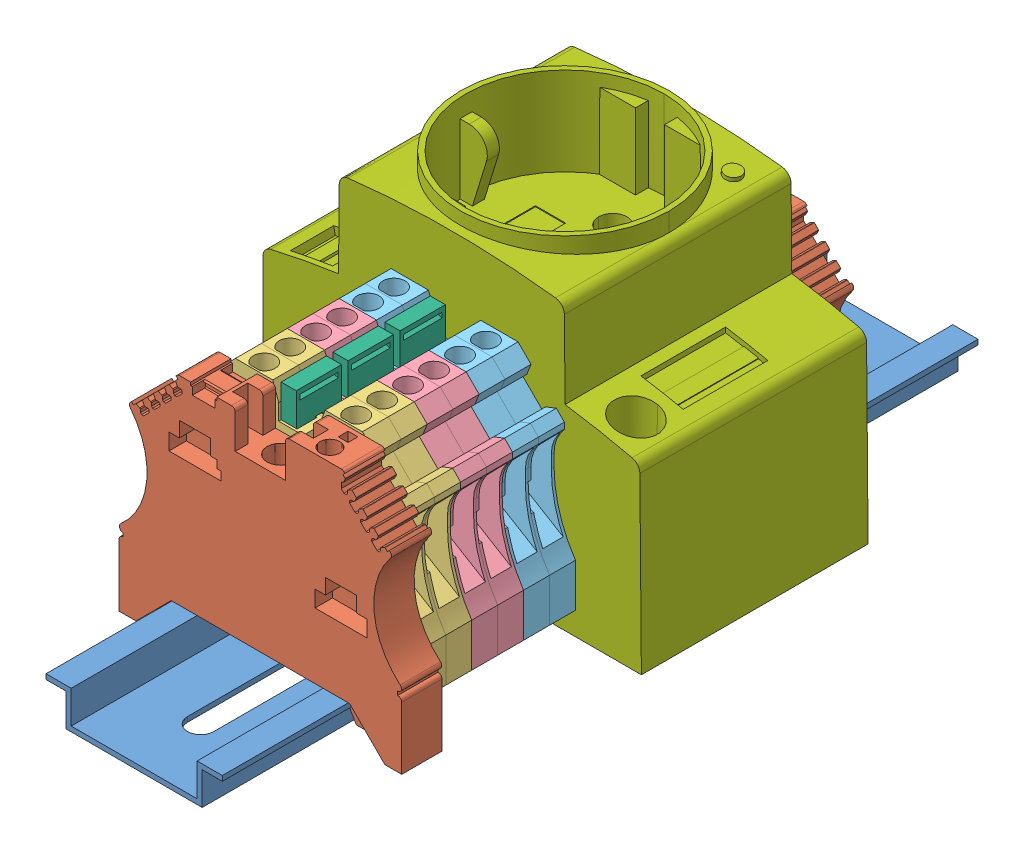
SolidWorks assembly Power Audio Schreibtisch-Klein, configuration Standard. Lengths in mm.
Overall size (75.48 67.56 150).
13 component instances, 7 part files, 39 mates.
Components (placement in the parent):
- Hutschiene-1: Hutschiene [150] at (-17.5 -7.5 -150) size (35 7.5 150)
- WEW_35_2-1: WEW_35_2 [Standard] at (-45.49 -7 -33) x (0 0 1) z (0 1 0) size (8 56.1 46.5)
- UT_2.5-1: UT_2.5 [Standard] at (-48.9989 10.6178 -38.15) x (0.992546 -0.121869 0) z (0 0 1) size (49.27 50.96 5.15)
- UT_2.5-2: UT_2.5 [Standard] at (-48.9989 10.6178 -33) x (0.992546 -0.121869 0) z (0 0 1) size (49.27 50.96 5.15)
- UT_2.5_BU-1: UT_2.5_BU [Standard] at (-48.9989 10.6178 -43.3) x (0.992546 -0.121869 0) z (0 0 1) size (49.27 50.96 5.15)
- UT_2.5_BU-2: UT_2.5_BU [Standard] at (-48.9989 10.6178 -48.45) x (0.992546 -0.121869 0) z (0 0 1) size (49.27 50.96 5.15)
- UT_2.5_PE-1: UT_2.5_PE [Standard] at (-48.9989 10.6178 -53.6) x (0.992546 -0.121869 0) z (0 0 1) size (49.27 50.96 5.15)
- UT_2.5_PE-2: UT_2.5_PE [Standard] at (-48.9989 10.6178 -58.75) x (0.992546 -0.121869 0) z (0 0 1) size (49.27 50.96 5.15)
- FBS_2-5-1: FBS_2-5 [Standard] at (-24.4072 49.175 -91.835) size (3 22.98 9)
- FBS_2-5-3: FBS_2-5 [Standard] at (-24.4072 49.175 -102.135) size (3 22.98 9)
- FBS_2-5-2: FBS_2-5 [Standard] at (-24.4072 49.175 -112.435) size (3 22.98 9)
- EO_CF_UT_LED-1: EO_CF_UT_LED [Standard] at (-87.6914 -21.0563 -88.65) size (75.48 61.64 45)
- WEW_35_2-2: WEW_35_2 [Standard] at (-45.61 -7 -116.9) x (0 0 1) z (0 1 0) size (8 56.1 46.5)
Mates (geometry in assembly coordinates):
- Deckungsgleich1: coincident aligned: plane of Hutschiene-1 through (-17.5 -7.5 0) normal (0 0 1); plane of assembly through (0 0 0) normal (0 0 1)
- Deckungsgleich2: coincident aligned: plane of Hutschiene-1 through (0 -1 0) normal (1 0 0); plane of assembly through (0 0 0) normal (1 0 0)
- Deckungsgleich3: coincident aligned: plane of Hutschiene-1 through (0 0 0) normal (0 1 0); plane of assembly through (0 0 0) normal (0 1 0)
- Deckungsgleich4: coincident anti-aligned: plane of Hutschiene-1 through (-30 0 0) normal (0 1 0); plane of WEW_35_2-1 through (0.26 0 -25) normal (0 -1 0)
- Tangential1: tangent anti-aligned: cylinder of WEW_35_2-1 through (-37 -1.4 -29) axis (0 0 1) radius 2; plane of Hutschiene-1 through (-35 0 0) normal (-1 0 0)
- Abstand1: distance = 25 mm aligned: plane of Hutschiene-1 through (-17.5 -7.5 0) normal (0 0 1); plane of WEW_35_2-1 through (-17.44 0 -25) normal (0 0 1)
- Deckungsgleich6: coincident anti-aligned: plane of UT_2.5-2 through (-0.3 0 -33) normal (0 0 1); plane of WEW_35_2-1 through (-17.44 0 -33) normal (0 0 -1)
- Deckungsgleich7: coincident anti-aligned: plane of UT_2.5-1 through (-0.3 0 -38.15) normal (0 0 1); plane of UT_2.5-2 through (-0.3 0 -38.15) normal (0 0 -1)
- Deckungsgleich8: coincident anti-aligned: plane of UT_2.5-1 through (-0.3 0 -43.3) normal (0 0 -1); plane of UT_2.5_BU-1 through (-0.3 0 -43.3) normal (0 0 1)
- Deckungsgleich9: coincident anti-aligned: plane of UT_2.5_BU-1 through (-0.3 0 -48.45) normal (0 0 -1); plane of UT_2.5_BU-2 through (-0.3 0 -48.45) normal (0 0 1)
- Deckungsgleich10: coincident anti-aligned: plane of UT_2.5_BU-2 through (-0.3 0 -53.6) normal (0 0 -1); plane of UT_2.5_PE-1 through (-0.3 0 -53.6) normal (0 0 1)
- Deckungsgleich11: coincident anti-aligned: plane of UT_2.5_PE-1 through (-0.3 0 -58.75) normal (0 0 -1); plane of UT_2.5_PE-2 through (-0.3 0 -58.75) normal (0 0 1)
- Deckungsgleich12: coincident anti-aligned: plane of UT_2.5_PE-2 through (-0.3 0 -63.9) normal (0 0 -1); plane of EO_CF_UT_LED-1 through (-18.35 2.45 -63.9) normal (0 0 1)
- Deckungsgleich13: coincident anti-aligned: plane of UT_2.5-2 through (-21.8 36.703 -33) normal (1 0 0); plane of FBS_2-5-1 through (-21.8 41.9423 -67.735) normal (-1 0 0)
- Deckungsgleich14: coincident anti-aligned: plane of UT_2.5-2 through (-18.65 21.85 -33.475) normal (0 0 -1); plane of FBS_2-5-1 through (-18.8 39.7 -33.475) normal (0 0 1)
- Deckungsgleich15: coincident aligned: plane of UT_2.5-2 through (-30.4 40 -33) normal (0 1 0); plane of FBS_2-5-1 through (-18.8 40 -12.975) normal (0 1 0)
- Deckungsgleich16: coincident anti-aligned: plane of UT_2.5_BU-1 through (-21.8 36.703 -43.3) normal (1 0 0); plane of FBS_2-5-3 through (-21.8 41.9423 -78.035) normal (-1 0 0)
- Deckungsgleich17: coincident anti-aligned: plane of UT_2.5_BU-1 through (-18.65 21.85 -43.775) normal (0 0 -1); plane of FBS_2-5-3 through (-18.8 39.7 -43.775) normal (0 0 1)
- Deckungsgleich18: coincident aligned: plane of UT_2.5_BU-1 through (-30.4 40 -43.3) normal (0 1 0); plane of FBS_2-5-3 through (-18.8 40 -23.275) normal (0 1 0)
- Deckungsgleich19: coincident anti-aligned: plane of UT_2.5_PE-1 through (-18.65 21.85 -54.075) normal (0 0 -1); plane of FBS_2-5-2 through (-18.8 39.7 -54.075) normal (0 0 1)
- Deckungsgleich20: coincident anti-aligned: plane of UT_2.5_PE-1 through (-21.8 36.703 -53.6) normal (1 0 0); plane of FBS_2-5-2 through (-21.8 41.9423 -88.335) normal (-1 0 0)
- Deckungsgleich21: coincident aligned: plane of UT_2.5_PE-1 through (-30.4 40 -53.6) normal (0 1 0); plane of FBS_2-5-2 through (-18.8 40 -33.575) normal (0 1 0)
- Deckungsgleich22: coincident anti-aligned: plane of Hutschiene-1 through (0 0 0) normal (0 1 0); plane of WEW_35_2-2 through (0.14 0 -108.9) normal (0 -1 0)
- Deckungsgleich23: coincident anti-aligned: plane of EO_CF_UT_LED-1 through (-18.35 2.45 -108.9) normal (0 0 -1); plane of WEW_35_2-2 through (-17.56 0 -108.9) normal (0 0 1)
- Tangential2: tangent anti-aligned: plane of Hutschiene-1 through (0 -1 0) normal (1 0 0); cylinder of WEW_35_2-2 through (2 -1.4 -112.9) axis (0 0 1) radius 2
- Deckungsgleich24: coincident anti-aligned: plane of Hutschiene-1 through (0 0 0) normal (0 1 0); plane of UT_2.5-2 through (-8 0 -33) normal (0 -1 0)
- Deckungsgleich25: coincident anti-aligned: plane of Hutschiene-1 through (-30 0 0) normal (0 1 0); plane of UT_2.5-1 through (-8 0 -38.15) normal (0 -1 0)
- Deckungsgleich26: coincident anti-aligned: plane of Hutschiene-1 through (-30 0 0) normal (0 1 0); plane of UT_2.5_BU-1 through (-8 0 -43.3) normal (0 -1 0)
- Deckungsgleich27: coincident anti-aligned: plane of Hutschiene-1 through (-30 0 0) normal (0 1 0); plane of UT_2.5_BU-2 through (-8 0 -48.45) normal (0 -1 0)
- Deckungsgleich28: coincident anti-aligned: plane of Hutschiene-1 through (-30 0 0) normal (0 1 0); plane of UT_2.5_PE-1 through (-8 0 -53.6) normal (0 -1 0)
- Deckungsgleich29: coincident anti-aligned: plane of Hutschiene-1 through (-30 0 0) normal (0 1 0); plane of UT_2.5_PE-2 through (-8 0 -58.75) normal (0 -1 0)
- Deckungsgleich30: coincident anti-aligned: plane of Hutschiene-1 through (0 0 0) normal (0 1 0); plane of EO_CF_UT_LED-1 through (-54.65 0 -90.8) normal (0 -1 0)
- Deckungsgleich31: coincident anti-aligned: plane of Hutschiene-1 through (-35 0 0) normal (-1 0 0); plane of UT_2.5-2 through (-35 -0.3 -33) normal (1 0 0)
- Deckungsgleich32: coincident anti-aligned: plane of Hutschiene-1 through (-35 0 0) normal (-1 0 0); plane of UT_2.5-1 through (-35 -0.3 -38.15) normal (1 0 0)
- Deckungsgleich33: coincident anti-aligned: plane of Hutschiene-1 through (-35 0 0) normal (-1 0 0); plane of UT_2.5_BU-1 through (-35 -0.3 -43.3) normal (1 0 0)
- Deckungsgleich34: coincident anti-aligned: plane of Hutschiene-1 through (-35 0 0) normal (-1 0 0); plane of UT_2.5_BU-2 through (-35 -0.3 -48.45) normal (1 0 0)
- Deckungsgleich35: coincident anti-aligned: plane of Hutschiene-1 through (-35 0 0) normal (-1 0 0); plane of UT_2.5_PE-1 through (-35 -0.3 -53.6) normal (1 0 0)
- Deckungsgleich36: coincident anti-aligned: plane of Hutschiene-1 through (-35 0 0) normal (-1 0 0); plane of UT_2.5_PE-2 through (-35 -0.3 -58.75) normal (1 0 0)
- Deckungsgleich37: coincident anti-aligned: plane of Hutschiene-1 through (-35 0 0) normal (-1 0 0); plane of EO_CF_UT_LED-1 through (-35 -41.451 -95.15) normal (1 0 0)
